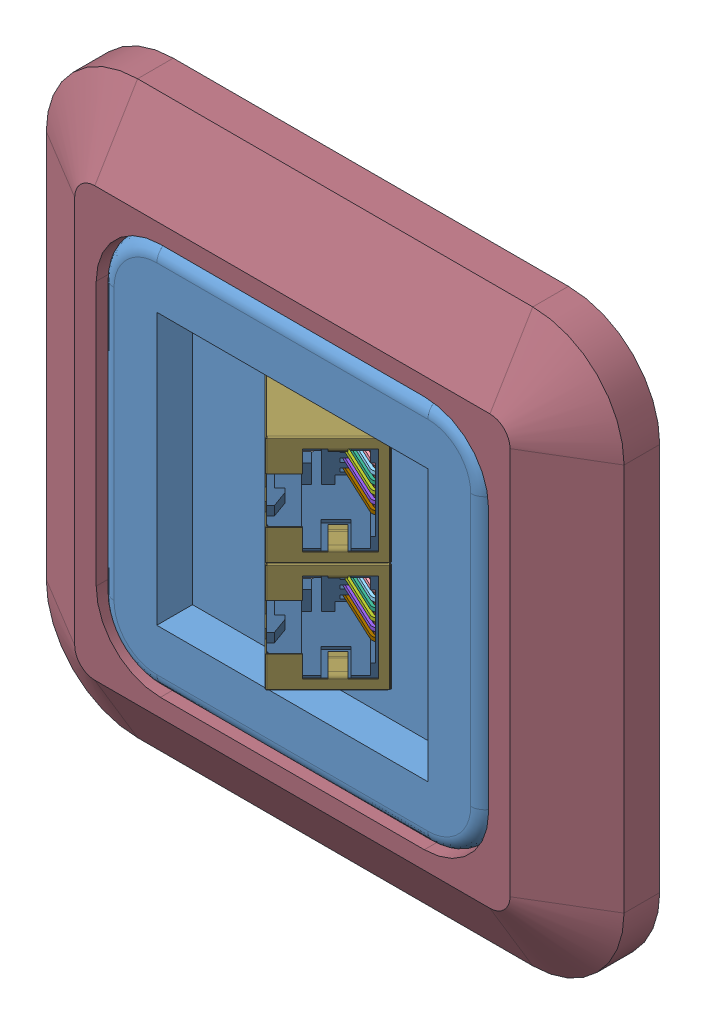
SolidWorks assembly Steckdose_1er-RJ, configuration Standard. Lengths in mm.
Overall size (81 80 25.23).
27 component instances, 13 part files, 3 mates.
Components (placement in the parent):
- Steckdose-RJ45-1: Steckdose-RJ45 [Standard] at (18.9082 -0.7233 10.2377) size (54 54 25.23)
  - Buchse-RJ45-1: Buchse-RJ45 [Standard] at (-88.9836 -48.9043 64.0274) size (54 54 6)
  - 65864-1: 65864 [Default] at (-11.8405 9.7148 53.1274) size (17.49 15.42 25.23)
    - 65864_01-1: 65864_01 [Default] at origin size (9.69 0.75 13.83)
    - 65864_02-1: 65864_02 [Default] at origin size (9.44 0.68 13.83)
    - 65864_03-1: 65864_03 [Default] at origin size (9.69 0.61 13.84)
    - 65864_04-1: 65864_04 [Default] at origin size (9.44 0.54 13.83)
    - 65864_05-1: 65864_05 [Default] at origin size (9.69 0.54 13.82)
    - 65864_06-1: 65864_06 [Default] at origin size (9.44 0.6 13.83)
    - 65864_07-1: 65864_07 [Default] at origin size (9.69 0.68 13.83)
    - 65864_08-1: 65864_08 [Default] at origin size (9.44 0.75 13.83)
    - 65864_09-1: 65864_09 [Default] at origin size (17.11 15.1 23.65)
    - 65864_10-1: 65864_10 [Default] at origin size (6.36 10.31 6.36)
    - 65864_11-1: 65864_11 [Default] at origin size (17.49 15.42 25.23)
  - 65864-2: 65864 [Default] at (-11.8405 -5.6852 53.1274) size (17.49 15.42 25.23)
    - 65864_01-1: 65864_01 [Default] at origin size (9.69 0.75 13.83)
    - 65864_02-1: 65864_02 [Default] at origin size (9.44 0.68 13.83)
    - 65864_03-1: 65864_03 [Default] at origin size (9.69 0.61 13.84)
    - 65864_04-1: 65864_04 [Default] at origin size (9.44 0.54 13.83)
    - 65864_05-1: 65864_05 [Default] at origin size (9.69 0.54 13.82)
    - 65864_06-1: 65864_06 [Default] at origin size (9.44 0.6 13.83)
    - 65864_07-1: 65864_07 [Default] at origin size (9.69 0.68 13.83)
    - 65864_08-1: 65864_08 [Default] at origin size (9.44 0.75 13.83)
    - 65864_09-1: 65864_09 [Default] at origin size (17.11 15.1 23.65)
    - 65864_10-1: 65864_10 [Default] at origin size (6.36 10.31 6.36)
    - 65864_11-1: 65864_11 [Default] at origin size (17.49 15.42 25.23)
- Wandplatte-1: Wandplatte [1er] at (-33.5773 -38.7085 74.2651) size (81 80 11)
Mates (geometry in assembly coordinates):
- Deckungsgleich1: coincident anti-aligned: plane of Steckdose-RJ45-1/Buchse-RJ45-1 through (-12.0773 -17.7085 68.2651) normal (0 0 -1); plane of Wandplatte-1 through (-11.5773 -17.2085 68.2651) normal (0 0 1)
- Abstand1: distance = 0.5 mm anti-aligned: plane of Steckdose-RJ45-1/Buchse-RJ45-1 through (-12.0773 28.2915 68.2651) normal (0 1 0); plane of Wandplatte-1 through (-11.5773 28.7915 68.2651) normal (0 -1 0)
- Abstand2: distance = 0.5 mm anti-aligned: plane of Steckdose-RJ45-1/Buchse-RJ45-1 through (33.9227 20.2915 68.2651) normal (1 0 0); plane of Wandplatte-1 through (34.4227 19.7915 68.2651) normal (-1 0 0)
